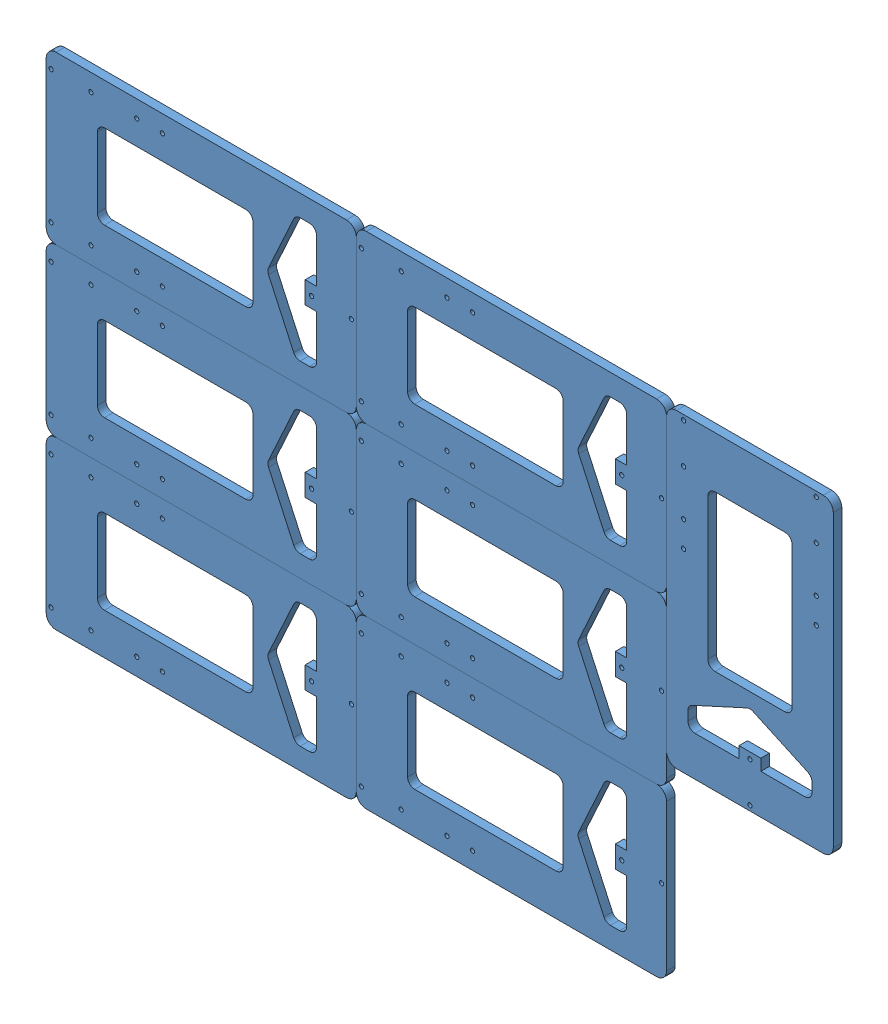
SolidWorks assembly 6mmSheet Layou, configuration Default. Lengths in mm.
Overall size (553.2 351.6 6).
7 component instances, 1 part files, 18 mates.
Components (placement in the parent):
- Y-frog-1: Y-frog [Default] at (214.0986 -3.6854 178.0993) size (218 117.2 6)
- Y-frog-2: Y-frog [Default] at (214.0986 -120.8854 178.0993) size (218 117.2 6)
- Y-frog-3: Y-frog [Default] at (214.0986 -238.0854 178.0993) size (218 117.2 6)
- Y-frog-4: Y-frog [Default] at (432.0986 -3.6854 178.0993) size (218 117.2 6)
- Y-frog-5: Y-frog [Default] at (251.3458 -6.951 178.0993) x (0 -1 0) z (0 0 1) size (218 117.2 6)
- Y-frog-6: Y-frog [Default] at (432.0986 -120.8854 178.0993) size (218 117.2 6)
- Y-frog-7: Y-frog [Default] at (432.0986 -238.0854 178.0993) size (218 117.2 6)
Mates (geometry in assembly coordinates):
- Coincident1: coincident aligned: plane of Y-frog-1 through (214.0986 -3.6854 184.0993) normal (0 0 1); plane of Y-frog-2 through (214.0986 -120.8854 184.0993) normal (0 0 1)
- Coincident2: coincident aligned: plane of Y-frog-2 through (214.0986 -120.8854 184.0993) normal (0 0 1); plane of Y-frog-3 through (214.0986 -238.0854 184.0993) normal (0 0 1)
- Coincident3: coincident aligned: plane of Y-frog-1 through (214.0986 -3.6854 184.0993) normal (0 0 1); plane of Y-frog-4 through (432.0986 -3.6854 184.0993) normal (0 0 1)
- Coincident4: coincident aligned: plane of Y-frog-4 through (432.0986 -3.6854 184.0993) normal (0 0 1); plane of Y-frog-5 through (251.3458 -6.951 184.0993) normal (0 0 1)
- Distance1: distance = 0 mm anti-aligned: plane of Y-frog-5 through (390.4894 252.6582 184.0993) normal (-1 0 0); plane of Y-frog-4 through (390.4894 252.6582 184.0993) normal (1 0 0)
- Coincident6: coincident aligned: plane of Y-frog-1 through (-45.5106 252.6582 184.0993) normal (-1 0 0); plane of Y-frog-2 through (-45.5106 135.4582 184.0993) normal (-1 0 0)
- Coincident7: coincident aligned: plane of Y-frog-2 through (-45.5106 135.4582 184.0993) normal (-1 0 0); plane of Y-frog-3 through (-45.5106 18.2582 184.0993) normal (-1 0 0)
- Coincident8: coincident aligned: plane of Y-frog-4 through (432.0986 -3.6854 184.0993) normal (0 0 1); plane of Y-frog-6 through (432.0986 -120.8854 184.0993) normal (0 0 1)
- Coincident9: coincident aligned: plane of Y-frog-2 through (-45.5106 18.2582 184.0993) normal (0 -1 0); plane of Y-frog-6 through (172.4894 18.2582 184.0993) normal (0 -1 0)
- Coincident10: coincident anti-aligned: plane of Y-frog-1 through (172.4894 252.6582 184.0993) normal (1 0 0); plane of Y-frog-4 through (172.4894 252.6582 184.0993) normal (-1 0 0)
- Coincident11: coincident anti-aligned: plane of Y-frog-1 through (-45.5106 135.4582 184.0993) normal (0 -1 0); plane of Y-frog-2 through (-45.5106 135.4582 184.0993) normal (0 1 0)
- Coincident12: coincident anti-aligned: plane of Y-frog-2 through (-45.5106 18.2582 184.0993) normal (0 -1 0); plane of Y-frog-3 through (-45.5106 18.2582 184.0993) normal (0 1 0)
- Coincident13: coincident anti-aligned: plane of Y-frog-2 through (172.4894 135.4582 184.0993) normal (1 0 0); plane of Y-frog-6 through (172.4894 135.4582 184.0993) normal (-1 0 0)
- Coincident14: coincident anti-aligned: plane of Y-frog-4 through (172.4894 135.4582 184.0993) normal (0 -1 0); plane of Y-frog-6 through (172.4894 135.4582 184.0993) normal (0 1 0)
- Coincident15: coincident aligned: plane of Y-frog-4 through (172.4894 252.6582 184.0993) normal (0 1 0); plane of Y-frog-5 through (507.6894 252.6582 184.0993) normal (0 1 0)
- Coincident17: coincident anti-aligned: plane of Y-frog-3 through (172.4894 18.2582 184.0993) normal (1 0 0); plane of Y-frog-7 through (172.4894 18.2582 184.0993) normal (-1 0 0)
- Coincident18: coincident anti-aligned: plane of Y-frog-6 through (172.4894 18.2582 184.0993) normal (0 -1 0); plane of Y-frog-7 through (172.4894 18.2582 184.0993) normal (0 1 0)
- Coincident19: coincident aligned: plane of Y-frog-6 through (432.0986 -120.8854 184.0993) normal (0 0 1); plane of Y-frog-7 through (432.0986 -238.0854 184.0993) normal (0 0 1)
